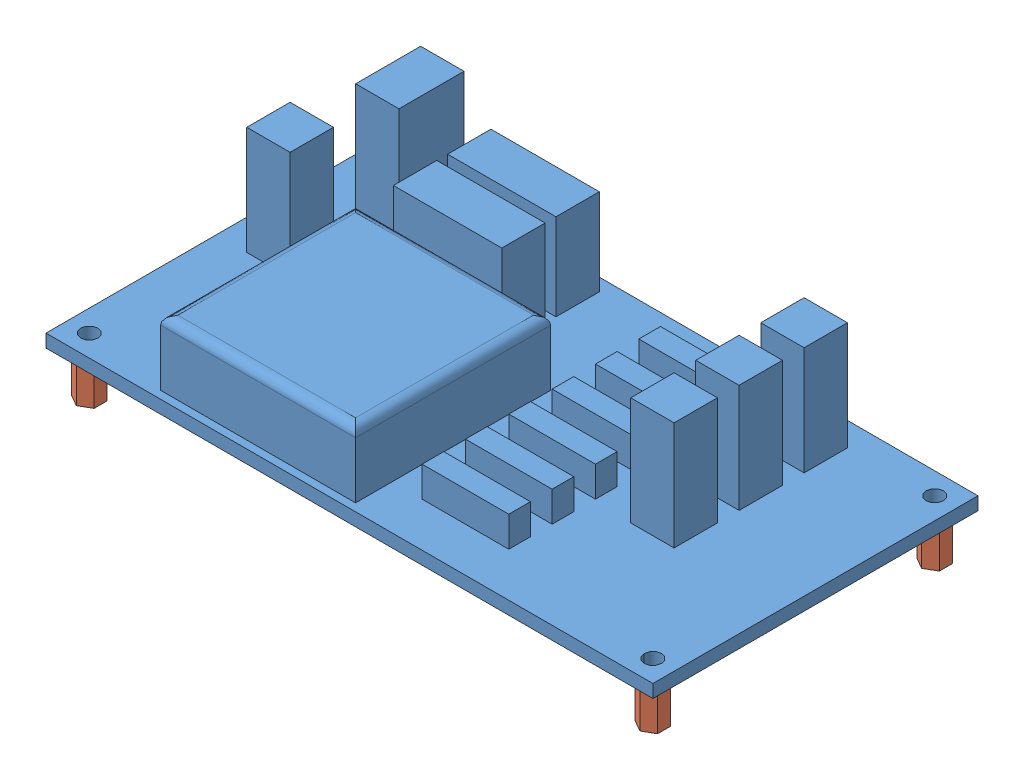
SolidWorks assembly Assemblage2, configuration Default. Lengths in mm.
Overall size (140 38 75.52).
5 component instances, 2 part files, 8 mates.
Components (placement in the parent):
- carte_puissance_2-1: carte_puissance_2 [Default] at (-78.4104 -5.515 36.4357) size (140 28 75.52)
- entretoise_M3_L10-1: entretoise_M3_L10 [Default] at (-73.4104 -15.515 31.4357) size (5.2 10 6)
- entretoise_M3_L10-2: entretoise_M3_L10 [Default] at (56.5896 -15.515 31.4357) size (5.2 10 6)
- entretoise_M3_L10-3: entretoise_M3_L10 [Default] at (56.5896 -15.515 -33.5643) size (5.2 10 6)
- entretoise_M3_L10-4: entretoise_M3_L10 [Default] at (-73.4104 -15.515 -33.5643) size (5.2 10 6)
Mates (geometry in assembly coordinates):
- Coaxiale1: concentric: cylinder of carte_puissance_2-1; cylinder of ?
- Coaxiale2: concentric: cylinder of carte_puissance_2-1; cylinder of ?
- Coaxiale3: concentric: cylinder of carte_puissance_2-1; cylinder of ?
- Coaxiale4: concentric: cylinder of carte_puissance_2-1; cylinder of ?
- Coïncidente1: coincident anti-aligned: plane of carte_puissance_2-1 through (-78.4104 -5.515 -38.5643) normal (0 -1 0); plane of ? through (-73.4104 -19.718 28.4357) normal (0 1 0)
- Coïncidente2: coincident anti-aligned: plane of carte_puissance_2-1 through (-78.4104 -5.515 -38.5643) normal (0 -1 0); plane of ? through (-73.4104 -17.4161 -36.5643) normal (0 1 0)
- Coïncidente3: coincident anti-aligned: plane of carte_puissance_2-1 through (-78.4104 -5.515 -38.5643) normal (0 -1 0); plane of ? through (56.5896 -16.7585 -36.5643) normal (0 1 0)
- Coïncidente4: coincident anti-aligned: plane of carte_puissance_2-1 through (-78.4104 -5.515 -38.5643) normal (0 -1 0); plane of ? through (56.5896 -40.4934 28.4357) normal (0 1 0)
